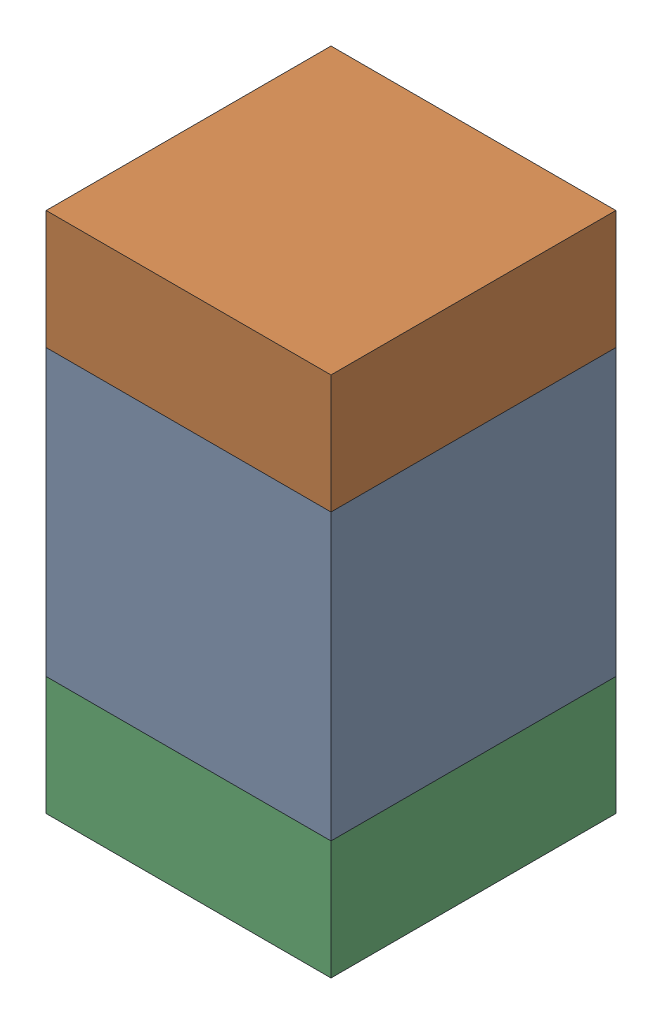
SolidWorks assembly C127_2PCB, configuration Default. Lengths in mm.
Overall size (0.6 1.1 0.6).
6 component instances, 2 part files, 0 mates.
Components (placement in the parent):
- 761606048-1: 761606048 [Default] at (102.9 99.7 0) size (0.6 0.6 0.6)
  - Extruded_9-1: Extruded_9 [Default] at origin size (0.6 0.6 0.6)
- 854785296-1: 854785296 [Default] at (102.9 100.125 0) size (0.6 0.25 0.6)
  - Extruded_10-1: Extruded_10 [Default] at origin size (0.6 0.25 0.6)
- 854785296-2: 854785296 [Default] at (102.9 99.275 0) size (0.6 0.25 0.6)
  - Extruded_10-1: Extruded_10 [Default] at origin size (0.6 0.25 0.6)
